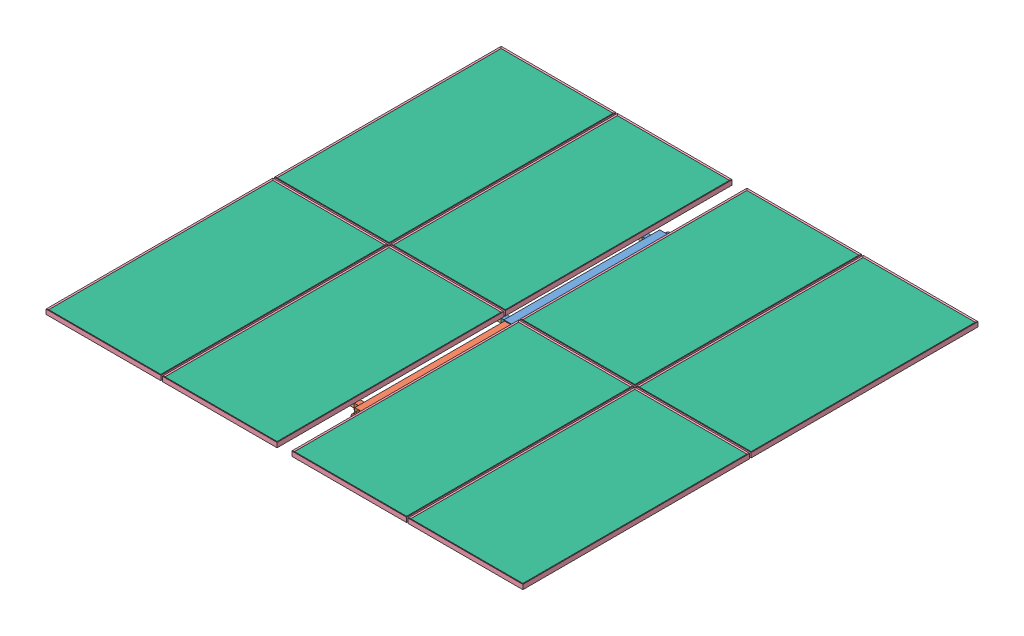
SolidWorks assembly SOLAR_ARRAY, configuration Default. Lengths in mm.
Overall size (4121.3 151.51 3933.6).
48 component instances, 7 part files, 66 mates.
Components (placement in the parent):
- SOLAR_FRAME_TELESCOPIC SLEEVE-1: SOLAR_FRAME_TELESCOPIC SLEEVE [Default] at (678.4072 800.4762 1616.3582) size (203.2 101.6 1384.3)
- SOLAR_FRAME_TELESCOPIC INSERT-1: SOLAR_FRAME_TELESCOPIC INSERT [Default] at (678.4072 800.4762 2911.7582) size (203.2 88.9 1612.9)
- SOLAR_FRAME_ARMBAR-1: SOLAR_FRAME_ARMBAR [Default] at (729.2072 800.4762 346.3582) x (0 0 1) z (-1 0 0) size (38.1 38.1 1828.8)
- SOLAR_FRAME_ARMBAR-2: SOLAR_FRAME_ARMBAR [Default] at (729.2072 800.4762 1565.5582) x (0 0 1) z (-1 0 0) size (38.1 38.1 1828.8)
- SOLAR_FRAME_ARMBAR-3: SOLAR_FRAME_ARMBAR [Default] at (729.2072 800.4762 2835.5582) x (0 0 -1) z (-1 0 0) size (38.1 38.1 1828.8)
- SOLAR_FRAME_ARMBAR-4: SOLAR_FRAME_ARMBAR [Default] at (627.6072 800.4762 346.3582) x (0 0 -1) z (1 0 0) size (38.1 38.1 1828.8)
- SOLAR_FRAME_ARMBAR-5: SOLAR_FRAME_ARMBAR [Default] at (627.6072 800.4762 1565.5582) x (0 0 -1) z (1 0 0) size (38.1 38.1 1828.8)
- SOLAR_FRAME_ARMBAR-6: SOLAR_FRAME_ARMBAR [Default] at (627.6072 800.4762 2835.5582) x (0 0 1) z (1 0 0) size (38.1 38.1 1828.8)
- SOLARPANEL-2: SOLARPANEL [Default] at (118.9072 880.5262 610.9582) size (992.9 40.66 1960.9)
  - SOLAR_PANEL_FRAM-1: SOLAR_PANEL_FRAM [Default] at origin size (992.9 40.66 1960.9)
  - SOLAR_PANEL_CELL-1: SOLAR_PANEL_CELL [Default] at (395 11.5 868.9962) x (0 0 -1) z (1 0 0) size (1956 21.55 988)
  - SOLAR_GLASS-1: SOLAR_GLASS [Default] at (0 11.8 0) x (0 0 1) z (-1 0 0) size (1956 3.2 988)
- SOLARPANEL-3: SOLARPANEL [Default] at (118.9072 880.5262 2583.6582) size (992.9 40.66 1960.9)
  - SOLAR_PANEL_FRAM-1: SOLAR_PANEL_FRAM [Default] at origin size (992.9 40.66 1960.9)
  - SOLAR_PANEL_CELL-1: SOLAR_PANEL_CELL [Default] at (395 11.5 868.9962) x (0 0 -1) z (1 0 0) size (1956 21.55 988)
  - SOLAR_GLASS-1: SOLAR_GLASS [Default] at (0 11.8 0) x (0 0 1) z (-1 0 0) size (1956 3.2 988)
- SOLARPANEL-4: SOLARPANEL [Default] at (1237.9072 880.5262 610.9582) size (992.9 40.66 1960.9)
  - SOLAR_PANEL_FRAM-1: SOLAR_PANEL_FRAM [Default] at origin size (992.9 40.66 1960.9)
  - SOLAR_PANEL_CELL-1: SOLAR_PANEL_CELL [Default] at (395 11.5 868.9962) x (0 0 -1) z (1 0 0) size (1956 21.55 988)
  - SOLAR_GLASS-1: SOLAR_GLASS [Default] at (0 11.8 0) x (0 0 1) z (-1 0 0) size (1956 3.2 988)
- SOLARPANEL-5: SOLARPANEL [Default] at (1237.9072 880.5262 2583.6582) size (992.9 40.66 1960.9)
  - SOLAR_PANEL_FRAM-1: SOLAR_PANEL_FRAM [Default] at origin size (992.9 40.66 1960.9)
  - SOLAR_PANEL_CELL-1: SOLAR_PANEL_CELL [Default] at (395 11.5 868.9962) x (0 0 -1) z (1 0 0) size (1956 21.55 988)
  - SOLAR_GLASS-1: SOLAR_GLASS [Default] at (0 11.8 0) x (0 0 1) z (-1 0 0) size (1956 3.2 988)
- SOLARPANEL-8: SOLARPANEL [Default] at (-885.7928 880.5262 610.9582) size (992.9 40.66 1960.9)
  - SOLAR_PANEL_FRAM-1: SOLAR_PANEL_FRAM [Default] at origin size (992.9 40.66 1960.9)
  - SOLAR_PANEL_CELL-1: SOLAR_PANEL_CELL [Default] at (395 11.5 868.9962) x (0 0 -1) z (1 0 0) size (1956 21.55 988)
  - SOLAR_GLASS-1: SOLAR_GLASS [Default] at (0 11.8 0) x (0 0 1) z (-1 0 0) size (1956 3.2 988)
- SOLARPANEL-9: SOLARPANEL [Default] at (-885.7928 880.5262 2583.6582) size (992.9 40.66 1960.9)
  - SOLAR_PANEL_FRAM-1: SOLAR_PANEL_FRAM [Default] at origin size (992.9 40.66 1960.9)
  - SOLAR_PANEL_CELL-1: SOLAR_PANEL_CELL [Default] at (395 11.5 868.9962) x (0 0 -1) z (1 0 0) size (1956 21.55 988)
  - SOLAR_GLASS-1: SOLAR_GLASS [Default] at (0 11.8 0) x (0 0 1) z (-1 0 0) size (1956 3.2 988)
- SOLARPANEL-10: SOLARPANEL [Default] at (2242.6072 880.5262 610.9582) size (992.9 40.66 1960.9)
  - SOLAR_PANEL_FRAM-1: SOLAR_PANEL_FRAM [Default] at origin size (992.9 40.66 1960.9)
  - SOLAR_PANEL_CELL-1: SOLAR_PANEL_CELL [Default] at (395 11.5 868.9962) x (0 0 -1) z (1 0 0) size (1956 21.55 988)
  - SOLAR_GLASS-1: SOLAR_GLASS [Default] at (0 11.8 0) x (0 0 1) z (-1 0 0) size (1956 3.2 988)
- SOLARPANEL-11: SOLARPANEL [Default] at (2242.6072 880.5262 2583.6582) size (992.9 40.66 1960.9)
  - SOLAR_PANEL_FRAM-1: SOLAR_PANEL_FRAM [Default] at origin size (992.9 40.66 1960.9)
  - SOLAR_PANEL_CELL-1: SOLAR_PANEL_CELL [Default] at (395 11.5 868.9962) x (0 0 -1) z (1 0 0) size (1956 21.55 988)
  - SOLAR_GLASS-1: SOLAR_GLASS [Default] at (0 11.8 0) x (0 0 1) z (-1 0 0) size (1956 3.2 988)
- Unistrut_41mm-5: Unistrut_41mm [Default] at (475.2072 840.0262 2949.8582) x (0 0 -1) z (1 0 0) size (2717.8 41 41)
- Unistrut_41mm-6: Unistrut_41mm [Default] at (-204.1928 840.0262 2949.8582) x (0 0 -1) z (1 0 0) size (2717.8 41 41)
- Unistrut_41mm-7: Unistrut_41mm [Default] at (-562.6928 840.0262 2949.8582) x (0 0 -1) z (1 0 0) size (2717.8 41 41)
- Unistrut_41mm-8: Unistrut_41mm [Default] at (-1056.4928 840.0262 2949.8582) x (0 0 -1) z (1 0 0) size (2717.8 41 41)
- Unistrut_41mm-9: Unistrut_41mm [Default] at (914.8072 840.0262 2949.8582) x (0 0 -1) z (1 0 0) size (2717.8 41 41)
- Unistrut_41mm-10: Unistrut_41mm [Default] at (1561.0072 840.0262 2949.8582) x (0 0 -1) z (1 0 0) size (2717.8 41 41)
- Unistrut_41mm-11: Unistrut_41mm [Default] at (1919.5072 840.0262 2949.8582) x (0 0 -1) z (1 0 0) size (2717.8 41 41)
- Unistrut_41mm-12: Unistrut_41mm [Default] at (2413.3072 840.0262 2949.8582) x (0 0 -1) z (1 0 0) size (2717.8 41 41)
Mates (geometry in assembly coordinates):
- Coincident1: coincident anti-aligned: plane of SOLAR_FRAME_TELESCOPIC SLEEVE-1 through (722.8572 844.9262 270.1582) normal (-1 0 0); plane of SOLAR_FRAME_TELESCOPIC INSERT-1 through (722.8572 844.9262 1336.9582) normal (1 0 0)
- Coincident2: coincident anti-aligned: plane of SOLAR_FRAME_TELESCOPIC SLEEVE-1 through (633.9572 844.9262 270.1582) normal (0 -1 0); plane of SOLAR_FRAME_TELESCOPIC INSERT-1 through (633.9572 844.9262 1336.9582) normal (0 1 0)
- Concentric1: concentric anti-aligned: circle of SOLAR_FRAME_TELESCOPIC INSERT-1; circle of SOLAR_FRAME_ARMBAR-3
- Coincident5: coincident anti-aligned: plane of SOLAR_FRAME_TELESCOPIC INSERT-1 through (780.0072 819.5262 2854.6082) normal (0 0 -1); plane of SOLAR_FRAME_ARMBAR-3 through (2558.0072 781.4262 2854.6082) normal (0 0 1)
- Coincident6: coincident anti-aligned: plane of SOLAR_FRAME_TELESCOPIC INSERT-1 through (780.0072 781.4262 2854.6082) normal (0 1 0); plane of SOLAR_FRAME_ARMBAR-3 through (2558.0072 781.4262 2854.6082) normal (0 -1 0)
- Coincident7: coincident anti-aligned: circle of SOLAR_FRAME_TELESCOPIC SLEEVE-1; circle of SOLAR_FRAME_ARMBAR-2
- Coincident8: coincident anti-aligned: plane of SOLAR_FRAME_TELESCOPIC SLEEVE-1 through (780.0072 781.4262 1584.6082) normal (0 1 0); plane of SOLAR_FRAME_ARMBAR-2 through (2558.0072 781.4262 1546.5082) normal (0 -1 0)
- Coincident9: coincident aligned: circle of SOLAR_FRAME_TELESCOPIC SLEEVE-1; circle of SOLAR_FRAME_ARMBAR-1
- Coincident10: coincident anti-aligned: plane of SOLAR_FRAME_TELESCOPIC SLEEVE-1 through (780.0072 781.4262 365.4082) normal (0 1 0); plane of SOLAR_FRAME_ARMBAR-1 through (2558.0072 781.4262 327.3082) normal (0 -1 0)
- Coincident13: coincident anti-aligned: circle of SOLAR_FRAME_TELESCOPIC SLEEVE-1; circle of SOLAR_FRAME_ARMBAR-4
- Coincident14: coincident anti-aligned: plane of SOLAR_FRAME_TELESCOPIC SLEEVE-1 through (576.8072 781.4262 327.3082) normal (0 1 0); plane of SOLAR_FRAME_ARMBAR-4 through (-1201.1928 781.4262 365.4082) normal (0 -1 0)
- Coincident16: coincident anti-aligned: circle of SOLAR_FRAME_TELESCOPIC SLEEVE-1; circle of SOLAR_FRAME_ARMBAR-5
- Coincident17: coincident anti-aligned: plane of SOLAR_FRAME_TELESCOPIC SLEEVE-1 through (576.8072 781.4262 1546.5082) normal (0 1 0); plane of SOLAR_FRAME_ARMBAR-5 through (-1201.1928 781.4262 1584.6082) normal (0 -1 0)
- Coincident18: coincident anti-aligned: circle of SOLAR_FRAME_TELESCOPIC INSERT-1; circle of SOLAR_FRAME_ARMBAR-6
- Coincident19: coincident anti-aligned: plane of SOLAR_FRAME_TELESCOPIC INSERT-1 through (576.8072 781.4262 2816.5082) normal (0 1 0); plane of SOLAR_FRAME_ARMBAR-6 through (-1201.1928 781.4262 2816.5082) normal (0 -1 0)
- Distance11: distance = 12.7 mm anti-aligned: plane of SOLARPANEL-2/SOLAR_PANEL_FRAM-1 through (615.1072 860.5262 1590.9582) normal (0 0 1); plane of SOLARPANEL-3/SOLAR_PANEL_FRAM-1 through (-377.2928 860.5262 1603.6582) normal (0 0 -1)
- Coincident39: coincident aligned: plane of SOLARPANEL-2/SOLAR_PANEL_FRAM-1 through (-377.0928 860.5262 1591.1582) normal (-1 0 0); plane of SOLARPANEL-3/SOLAR_PANEL_FRAM-1 through (-377.0928 860.5262 3563.8582) normal (-1 0 0)
- Coincident40: coincident aligned: plane of SOLARPANEL-2/SOLAR_PANEL_FRAM-1 through (-377.2928 860.5262 -334.0418) normal (0 -1 0); plane of SOLARPANEL-3/SOLAR_PANEL_FRAM-1 through (-377.2928 860.5262 1638.6582) normal (0 -1 0)
- Coincident41: coincident aligned: plane of SOLARPANEL-4/SOLAR_PANEL_FRAM-1 through (741.9072 860.5262 1591.1582) normal (-1 0 0); plane of SOLARPANEL-5/SOLAR_PANEL_FRAM-1 through (741.9072 860.5262 3563.8582) normal (-1 0 0)
- Distance8: distance = 12.7 mm anti-aligned: plane of SOLARPANEL-4/SOLAR_PANEL_FRAM-1 through (1734.1072 860.5262 1590.9582) normal (0 0 1); plane of SOLARPANEL-5/SOLAR_PANEL_FRAM-1 through (741.7072 860.5262 1603.6582) normal (0 0 -1)
- Coincident43: coincident aligned: plane of SOLARPANEL-4/SOLAR_PANEL_FRAM-1 through (741.7072 860.5262 -334.0418) normal (0 -1 0); plane of SOLARPANEL-5/SOLAR_PANEL_FRAM-1 through (741.7072 860.5262 1638.6582) normal (0 -1 0)
- Coincident47: coincident aligned: plane of SOLARPANEL-8/SOLAR_PANEL_FRAM-1 through (-1381.7928 860.5262 1591.1582) normal (-1 0 0); plane of SOLARPANEL-9/SOLAR_PANEL_FRAM-1 through (-1381.7928 860.5262 3563.8582) normal (-1 0 0)
- Distance7: distance = 12.7 mm anti-aligned: plane of SOLARPANEL-8/SOLAR_PANEL_FRAM-1 through (-389.5928 860.5262 1590.9582) normal (0 0 1); plane of SOLARPANEL-9/SOLAR_PANEL_FRAM-1 through (-1381.9928 860.5262 1603.6582) normal (0 0 -1)
- Coincident49: coincident aligned: plane of SOLARPANEL-8/SOLAR_PANEL_FRAM-1 through (-1381.9928 860.5262 -334.0418) normal (0 -1 0); plane of SOLARPANEL-9/SOLAR_PANEL_FRAM-1 through (-1381.9928 860.5262 1638.6582) normal (0 -1 0)
- Coincident50: coincident aligned: plane of SOLARPANEL-10/SOLAR_PANEL_FRAM-1 through (1746.6072 860.5262 1591.1582) normal (-1 0 0); plane of SOLARPANEL-11/SOLAR_PANEL_FRAM-1 through (1746.6072 860.5262 3563.8582) normal (-1 0 0)
- Distance9: distance = 12.7 mm anti-aligned: plane of SOLARPANEL-10/SOLAR_PANEL_FRAM-1 through (2738.8072 860.5262 1590.9582) normal (0 0 1); plane of SOLARPANEL-11/SOLAR_PANEL_FRAM-1 through (1746.4072 860.5262 1603.6582) normal (0 0 -1)
- Coincident52: coincident aligned: plane of SOLARPANEL-10/SOLAR_PANEL_FRAM-1 through (1746.4072 860.5262 -334.0418) normal (0 -1 0); plane of SOLARPANEL-11/SOLAR_PANEL_FRAM-1 through (1746.4072 860.5262 1638.6582) normal (0 -1 0)
- Distance12: distance = 12.7 mm anti-aligned: plane of SOLARPANEL-3/SOLAR_PANEL_FRAM-1 through (-377.0928 860.5262 3563.8582) normal (-1 0 0); plane of SOLARPANEL-9/SOLAR_PANEL_FRAM-1 through (-389.7928 860.5262 1603.4582) normal (1 0 0)
- Coincident54: coincident aligned: plane of SOLARPANEL-3/SOLAR_PANEL_FRAM-1 through (615.1072 860.5262 3563.6582) normal (0 0 1); plane of SOLARPANEL-9/SOLAR_PANEL_FRAM-1 through (-389.5928 860.5262 3563.6582) normal (0 0 1)
- Distance10: distance = 12.7 mm anti-aligned: plane of SOLARPANEL-5/SOLAR_PANEL_FRAM-1 through (1733.9072 860.5262 1603.4582) normal (1 0 0); plane of SOLARPANEL-11/SOLAR_PANEL_FRAM-1 through (1746.6072 860.5262 3563.8582) normal (-1 0 0)
- Coincident56: coincident aligned: plane of SOLARPANEL-5/SOLAR_PANEL_FRAM-1 through (1734.1072 860.5262 3563.6582) normal (0 0 1); plane of SOLARPANEL-11/SOLAR_PANEL_FRAM-1 through (2738.8072 860.5262 3563.6582) normal (0 0 1)
- Coincident57: coincident aligned: plane of SOLARPANEL-5/SOLAR_PANEL_FRAM-1 through (741.7072 860.5262 1638.6582) normal (0 -1 0); plane of SOLARPANEL-11/SOLAR_PANEL_FRAM-1 through (1746.4072 860.5262 1638.6582) normal (0 -1 0)
- Coincident58: coincident aligned: plane of SOLARPANEL-3/SOLAR_PANEL_FRAM-1 through (-377.2928 860.5262 1638.6582) normal (0 -1 0); plane of SOLARPANEL-9/SOLAR_PANEL_FRAM-1 through (-1381.9928 860.5262 1638.6582) normal (0 -1 0)
- Distance5: distance = 1358.9 mm: line of SOLARPANEL-2/SOLAR_PANEL_FRAM-1 through (614.9072 900.5262 1590.9582) axis (0 -1 0); plane of SOLAR_FRAME_TELESCOPIC SLEEVE-1 through (678.4072 800.4762 232.0582) normal (0 0 -1)
- Distance6: distance = 127 mm anti-aligned: plane of SOLARPANEL-2/SOLAR_PANEL_FRAM-1 through (614.9072 860.5262 -369.2418) normal (1 0 0); plane of SOLARPANEL-4/SOLAR_PANEL_FRAM-1 through (741.9072 860.5262 1591.1582) normal (-1 0 0)
- Parallel3: parallel anti-aligned: plane of SOLAR_FRAME_TELESCOPIC SLEEVE-1 through (627.6072 851.2762 270.1582) normal (-1 0 0); plane of SOLARPANEL-2/SOLAR_PANEL_FRAM-1 through (614.9072 860.5262 -369.2418) normal (1 0 0)
- Coincident64: coincident aligned: plane of SOLARPANEL-3/SOLAR_PANEL_FRAM-1 through (615.1072 860.5262 3563.6582) normal (0 0 1); plane of SOLARPANEL-5/SOLAR_PANEL_FRAM-1 through (1734.1072 860.5262 3563.6582) normal (0 0 1)
- Coincident65: coincident anti-aligned: plane of SOLAR_FRAME_ARMBAR-5 through (-1201.1928 819.5262 1584.6082) normal (0 1 0); plane of Unistrut_41mm-5 through (494.7072 819.5262 232.0582) normal (0 -1 0)
- Parallel4: parallel anti-aligned: plane of SOLAR_FRAME_TELESCOPIC SLEEVE-1 through (627.6072 851.2762 270.1582) normal (-1 0 0); plane of Unistrut_41mm-5 through (495.7072 820.5262 232.0582) normal (1 0 0)
- Coincident67: coincident aligned: plane of SOLAR_FRAME_TELESCOPIC SLEEVE-1 through (678.4072 800.4762 232.0582) normal (0 0 -1); plane of Unistrut_41mm-5 through (455.7072 859.5262 232.0582) normal (0 0 -1)
- Distance13: distance = 152.4 mm: moEndPointRef_w of Unistrut_41mm-5; plane of SOLAR_FRAME_TELESCOPIC SLEEVE-1 through (627.6072 851.2762 270.1582) normal (-1 0 0)
- Coincident69: coincident aligned: plane of Unistrut_41mm-11 through (1900.0072 859.5262 232.0582) normal (0 0 -1); plane of Unistrut_41mm-12 through (2393.8072 859.5262 232.0582) normal (0 0 -1)
- Coincident70: coincident aligned: plane of Unistrut_41mm-10 through (1541.5072 859.5262 232.0582) normal (0 0 -1); plane of Unistrut_41mm-11 through (1900.0072 859.5262 232.0582) normal (0 0 -1)
- Coincident71: coincident aligned: plane of Unistrut_41mm-9 through (895.3072 859.5262 232.0582) normal (0 0 -1); plane of Unistrut_41mm-10 through (1541.5072 859.5262 232.0582) normal (0 0 -1)
- Coincident72: coincident aligned: plane of SOLAR_FRAME_TELESCOPIC SLEEVE-1 through (678.4072 800.4762 232.0582) normal (0 0 -1); plane of Unistrut_41mm-9 through (895.3072 859.5262 232.0582) normal (0 0 -1)
- Coincident73: coincident aligned: plane of Unistrut_41mm-5 through (455.7072 859.5262 232.0582) normal (0 0 -1); plane of Unistrut_41mm-6 through (-223.6928 859.5262 232.0582) normal (0 0 -1)
- Coincident74: coincident aligned: plane of Unistrut_41mm-6 through (-223.6928 859.5262 232.0582) normal (0 0 -1); plane of Unistrut_41mm-7 through (-582.1928 859.5262 232.0582) normal (0 0 -1)
- Coincident75: coincident aligned: plane of Unistrut_41mm-7 through (-582.1928 859.5262 232.0582) normal (0 0 -1); plane of Unistrut_41mm-8 through (-1075.9928 859.5262 232.0582) normal (0 0 -1)
- Coincident76: coincident aligned: plane of Unistrut_41mm-5 through (494.7072 819.5262 232.0582) normal (0 -1 0); plane of Unistrut_41mm-6 through (-184.6928 819.5262 232.0582) normal (0 -1 0)
- Coincident77: coincident aligned: plane of Unistrut_41mm-6 through (-184.6928 819.5262 232.0582) normal (0 -1 0); plane of Unistrut_41mm-7 through (-543.1928 819.5262 232.0582) normal (0 -1 0)
- Coincident78: coincident aligned: plane of Unistrut_41mm-7 through (-543.1928 819.5262 232.0582) normal (0 -1 0); plane of Unistrut_41mm-8 through (-1036.9928 819.5262 232.0582) normal (0 -1 0)
- Coincident79: coincident anti-aligned: plane of SOLAR_FRAME_ARMBAR-2 through (2558.0072 819.5262 1546.5082) normal (0 1 0); plane of Unistrut_41mm-9 through (934.3072 819.5262 232.0582) normal (0 -1 0)
- Coincident80: coincident aligned: plane of Unistrut_41mm-9 through (934.3072 819.5262 232.0582) normal (0 -1 0); plane of Unistrut_41mm-10 through (1580.5072 819.5262 232.0582) normal (0 -1 0)
- Coincident81: coincident aligned: plane of Unistrut_41mm-10 through (1580.5072 819.5262 232.0582) normal (0 -1 0); plane of Unistrut_41mm-11 through (1939.0072 819.5262 232.0582) normal (0 -1 0)
- Coincident82: coincident aligned: plane of Unistrut_41mm-11 through (1939.0072 819.5262 232.0582) normal (0 -1 0); plane of Unistrut_41mm-12 through (2432.8072 819.5262 232.0582) normal (0 -1 0)
- Coincident83: coincident anti-aligned: plane of SOLARPANEL-4/SOLAR_PANEL_FRAM-1 through (741.7072 860.5262 -334.0418) normal (0 -1 0); plane of Unistrut_41mm-9 through (902.8072 860.5262 232.0582) normal (0 1 0)
- Coincident84: coincident anti-aligned: plane of SOLARPANEL-2/SOLAR_PANEL_FRAM-1 through (-377.2928 860.5262 -334.0418) normal (0 -1 0); plane of Unistrut_41mm-5 through (494.7072 860.5262 232.0582) normal (0 1 0)
- Distance14: distance = 12.7 mm anti-aligned: plane of SOLARPANEL-2/SOLAR_PANEL_FRAM-1 through (614.9072 860.5262 -369.2418) normal (1 0 0); plane of SOLAR_FRAME_TELESCOPIC SLEEVE-1 through (627.6072 851.2762 270.1582) normal (-1 0 0)
- Distance15: distance = 304.8 mm aligned: plane of SOLARPANEL-10/SOLAR_PANEL_FRAM-1 through (2738.6072 860.5262 -369.2418) normal (1 0 0); plane of Unistrut_41mm-12 through (2433.8072 820.5262 232.0582) normal (1 0 0)
- Distance16: distance = 152.4 mm aligned: plane of SOLARPANEL-10/SOLAR_PANEL_FRAM-1 through (1746.6072 860.5262 1591.1582) normal (-1 0 0); plane of Unistrut_41mm-11 through (1899.0072 820.5262 232.0582) normal (-1 0 0)
- Distance17: distance = 152.4 mm aligned: plane of SOLARPANEL-4/SOLAR_PANEL_FRAM-1 through (1733.9072 860.5262 -369.2418) normal (1 0 0); plane of Unistrut_41mm-10 through (1581.5072 820.5262 232.0582) normal (1 0 0)
- Distance18: distance = 152.4 mm aligned: plane of SOLARPANEL-4/SOLAR_PANEL_FRAM-1 through (741.9072 860.5262 1591.1582) normal (-1 0 0); plane of Unistrut_41mm-9 through (894.3072 820.5262 232.0582) normal (-1 0 0)
- Distance20: distance = 152.4 mm aligned: plane of SOLARPANEL-2/SOLAR_PANEL_FRAM-1 through (-377.0928 860.5262 1591.1582) normal (-1 0 0); plane of Unistrut_41mm-6 through (-224.6928 820.5262 232.0582) normal (-1 0 0)
- Distance21: distance = 152.4 mm aligned: plane of SOLARPANEL-8/SOLAR_PANEL_FRAM-1 through (-389.7928 860.5262 -369.2418) normal (1 0 0); plane of Unistrut_41mm-7 through (-542.1928 820.5262 232.0582) normal (1 0 0)
- Distance22: distance = 304.8 mm aligned: plane of SOLARPANEL-8/SOLAR_PANEL_FRAM-1 through (-1381.7928 860.5262 1591.1582) normal (-1 0 0); plane of Unistrut_41mm-8 through (-1076.9928 820.5262 232.0582) normal (-1 0 0)
- Distance26: distance = 95.25 mm aligned: plane of SOLAR_FRAME_ARMBAR-6 through (-1201.1928 781.4262 2854.6082) normal (0 0 1); plane of Unistrut_41mm-5 through (455.7072 859.5262 2949.8582) normal (0 0 1)
